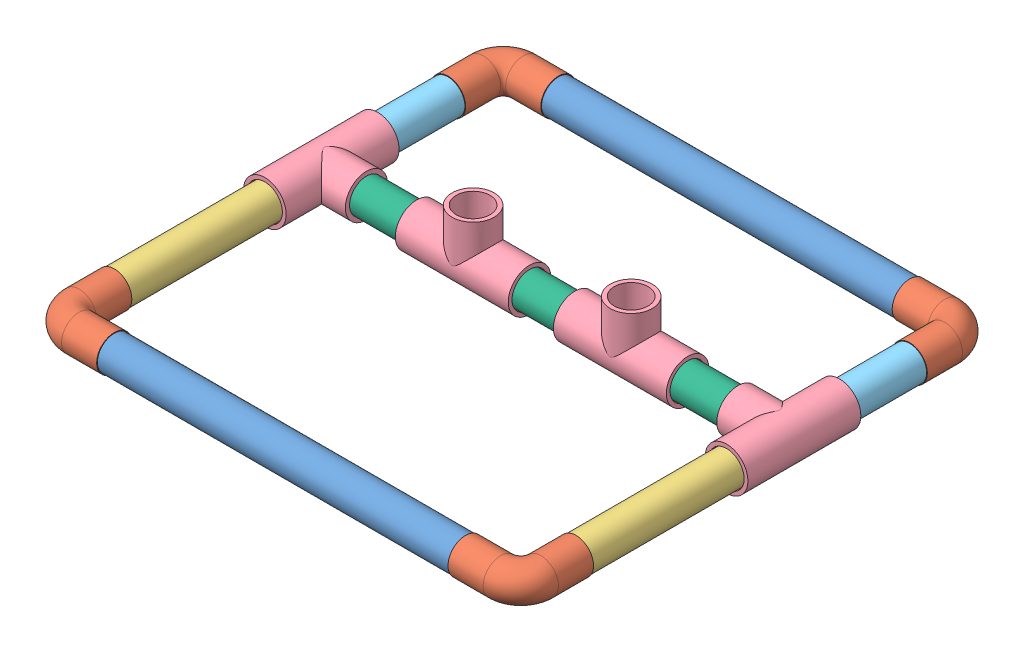
SolidWorks assembly basic_structure_left, configuration Default. Lengths in mm.
Overall size (320.45 128.03 303.21).
17 component instances, 6 part files, 30 mates.
Components (placement in the parent):
- PVC_tube_10-1: PVC_tube_10 [Default] at origin size (254 21.34 21.34)
- PVC_90-1: PVC_90 [Default] at (1.5875 0 -17.1322) x (-1 0 0) z (0 -1 0) size (46.04 46.04 22.23)
- PVC_90-2: PVC_90 [Default] at (-255.5875 0 -17.1322) x (1 0 0) z (0 1 0) size (46.04 46.04 22.23)
- PVC_tube_5-1: PVC_tube_5 [Default] at (19.05 0 -146.05) x (0 0 -1) z (-0.258772 -0.965938 0) size (127 21.34 21.34)
- PVC_tee-1: PVC_tee [Default] at (19.05 0 -165.8938) x (0 0 -1) z (0 1 0) size (71.44 48.76 26.99)
- PVC_tube_3-1: PVC_tube_3 [Default] at (19.05 0 -261.9375) x (0 0 -1) z (1 0 0) size (76.2 21.34 21.34)
- PVC_90-3: PVC_90 [Default] at (1.9178 0 -263.525) x (0 0 1) z (0 -1 0) size (46.04 46.04 22.23)
- PVC_tube_10-2: PVC_tube_10 [Default] at (0 0 -280.9875) size (254 21.34 21.34)
- PVC_90-4: PVC_90 [Default] at (-255.5875 0 -263.8553) x (1 0 0) z (0 -1 0) size (46.04 46.04 22.23)
- PVC_tee-2: PVC_tee [Default] at (-273.05 0 -165.8938) x (0 0 -1) z (0 -1 0) size (71.44 48.76 26.99)
- PVC_tube_3-2: PVC_tube_3 [Default] at (-273.05 0 -185.7375) x (0 0 1) z (0.996828 -0.079586 0) size (76.2 21.34 21.34)
- PVC_tube_5-2: PVC_tube_5 [Default] at (-273.05 0 -19.05) x (0 0 1) z (-0.574029 0.818835 0) size (127 21.34 21.34)
- PVC_tube_2.5-1: PVC_tube_2.5 [Default] at (-196.85 0 -165.8938) x (1 0 0) z (0 -0.97364 0.228092) size (63.5 21.34 21.34)
- PVC_tube_2.5-2: PVC_tube_2.5 [Default] at (-93.6625 0 -165.8938) x (1 0 0) z (0 -0.968379 0.249483) size (63.5 21.34 21.34)
- PVC_tube_2.5-3: PVC_tube_2.5 [Default] at (6.35 0 -165.8938) size (63.5 21.34 21.34)
- PVC_tee-6: PVC_tee [Default] at (-177.0062 0 -165.8938) size (71.44 48.76 26.99)
- PVC_tee-7: PVC_tee [Default] at (-76.9938 0 -165.8938) size (71.44 48.76 26.99)
Mates (geometry in assembly coordinates):
- Concentric1: concentric aligned: circle of PVC_tube_10-1; circle of PVC_90-1
- Distance1: distance = 15.875 mm anti-aligned: plane of PVC_tube_10-1 through (0 0 0) normal (1 0 0); plane of PVC_90-1 through (-15.875 0 0) normal (-1 0 0)
- Concentric2: concentric anti-aligned: circle of PVC_tube_10-1; circle of PVC_90-2
- Distance2: distance = 15.875 mm anti-aligned: plane of PVC_tube_10-1 through (-254 0 0) normal (-1 0 0); plane of PVC_90-2 through (-238.125 0 0) normal (1 0 0)
- Concentric3: concentric anti-aligned: circle of PVC_90-1; circle of PVC_tube_5-1
- Distance3: distance = 15.875 mm anti-aligned: plane of PVC_tube_5-1 through (19.05 0 -19.05) normal (0 0 1); plane of PVC_90-1 through (19.05 0 -34.925) normal (0 0 -1)
- Concentric4: concentric aligned: circle of PVC_tube_5-1; circle of PVC_tee-1
- Distance4: distance = 15.875 mm anti-aligned: plane of PVC_tee-1 through (19.05 0 -130.175) normal (0 0 1); plane of PVC_tube_5-1 through (19.05 0 -146.05) normal (0 0 -1)
- Concentric5: concentric aligned: circle of PVC_tee-1; circle of PVC_tube_3-1
- Distance5: distance = 15.875 mm anti-aligned: plane of PVC_tube_3-1 through (19.05 0 -185.7375) normal (0 0 1); plane of PVC_tee-1 through (19.05 0 -201.6125) normal (0 0 -1)
- Concentric7: concentric anti-aligned: circle of PVC_tube_3-1; circle of PVC_90-3
- Distance6: distance = 15.875 mm anti-aligned: plane of PVC_90-3 through (19.05 0 -246.0625) normal (0 0 1); plane of PVC_tube_3-1 through (19.05 0 -261.9375) normal (0 0 -1)
- Concentric8: concentric anti-aligned: circle of PVC_90-3; circle of PVC_tube_10-2
- Distance7: distance = 15.875 mm anti-aligned: plane of PVC_tube_10-2 through (0 0 -280.9875) normal (1 0 0); plane of PVC_90-3 through (-15.875 0 -280.9875) normal (-1 0 0)
- Distance8: distance = 15.875 mm anti-aligned: plane of PVC_90-4 through (-238.125 0 -280.9875) normal (1 0 0); plane of PVC_tube_10-2 through (-254 0 -280.9875) normal (-1 0 0)
- Concentric9: concentric aligned: circle of PVC_tube_10-2; circle of PVC_90-4
- Concentric10: concentric aligned: cylinder of PVC_90-4 through (-273.05 0 -246.0625) axis (0 0 -1) radius 11.1125; circle of PVC_tee-2
- Concentric11: concentric anti-aligned: circle of PVC_90-4; circle of PVC_tube_3-2
- Distance10: distance = 15.875 mm anti-aligned: plane of PVC_tube_3-2 through (-273.05 0 -261.9375) normal (0 0 -1); plane of PVC_90-4 through (-273.05 0 -246.0625) normal (0 0 1)
- Distance11: distance = 15.875 mm anti-aligned: plane of PVC_tee-2 through (-273.05 0 -201.6125) normal (0 0 -1); plane of PVC_tube_3-2 through (-273.05 0 -185.7375) normal (0 0 1)
- Concentric12: concentric anti-aligned: circle of PVC_tee-2; circle of PVC_tube_5-2
- Distance13: distance = 15.875 mm anti-aligned: plane of PVC_tube_5-2 through (-273.05 0 -19.05) normal (0 0 1); plane of PVC_90-2 through (-273.05 0 -34.925) normal (0 0 -1)
- Concentric13: concentric aligned: circle of PVC_tee-2; cylinder of PVC_tube_2.5-1 through (-260.35 0 -165.8938) axis (1 0 0) radius 10.668
- Distance14: distance = 15.875 mm anti-aligned: plane of PVC_tube_2.5-1 through (-260.35 0 -165.8938) normal (-1 0 0); plane of PVC_tee-2 through (-244.475 0 -165.8938) normal (1 0 0)
- Concentric17: concentric anti-aligned: circle of PVC_tee-1; circle of PVC_tube_2.5-3
- Distance18: distance = 15.875 mm anti-aligned: plane of PVC_tube_2.5-3 through (6.35 0 -165.8938) normal (1 0 0); plane of PVC_tee-1 through (-9.525 0 -165.8938) normal (-1 0 0)
- Concentric18: concentric aligned: circle of PVC_tube_2.5-3; circle of PVC_tee-7
- Distance19: distance = 15.875 mm anti-aligned: plane of PVC_tee-7 through (-41.275 0 -165.8938) normal (1 0 0); plane of PVC_tube_2.5-3 through (-57.15 0 -165.8938) normal (-1 0 0)
- Concentric19: concentric aligned: circle of PVC_tube_2.5-1; circle of PVC_tee-6
- Distance20: distance = 15.875 mm anti-aligned: plane of PVC_tee-6 through (-212.725 0 -165.8938) normal (-1 0 0); plane of PVC_tube_2.5-1 through (-196.85 0 -165.8938) normal (1 0 0)
